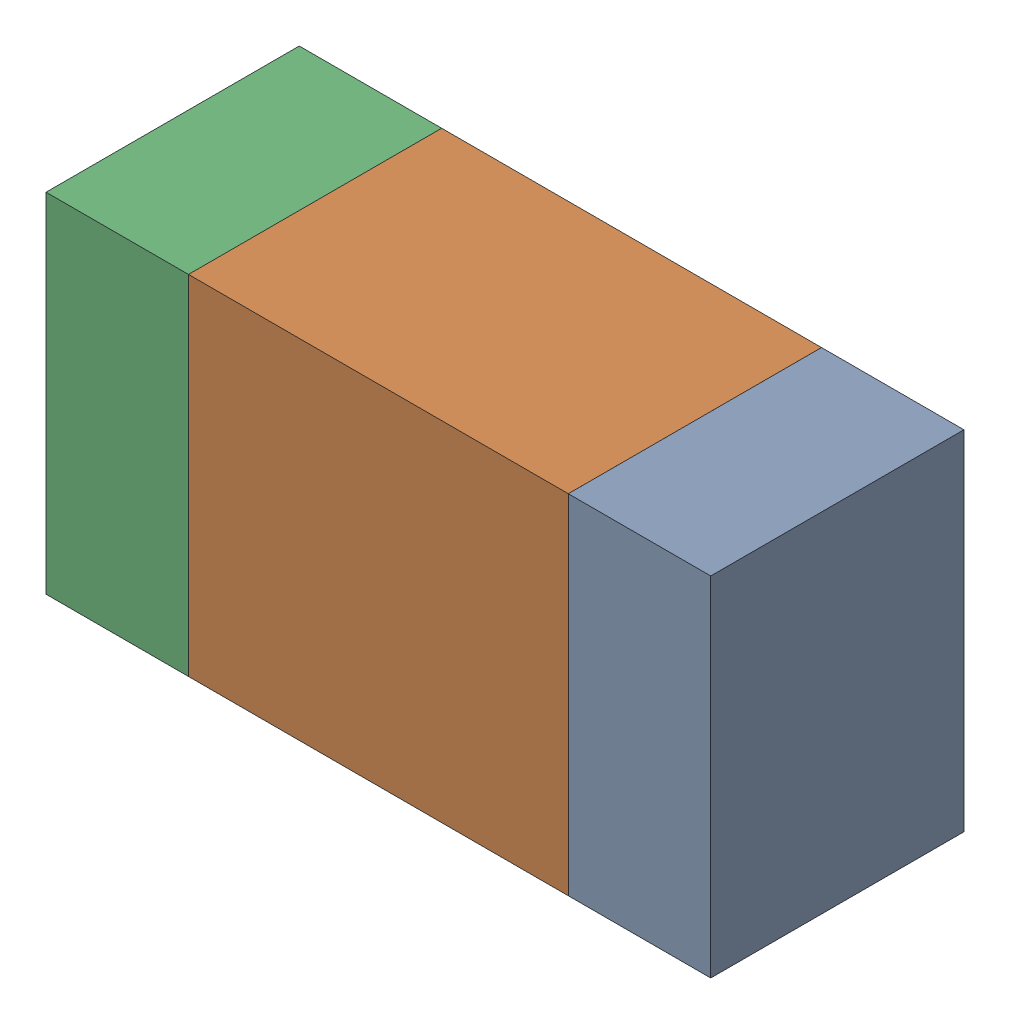
SolidWorks assembly R310_2PCB, configuration Default. Lengths in mm.
Overall size (1.05 0.55 0.4).
6 component instances, 2 part files, 0 mates.
Components (placement in the parent):
- 854785432-1: 854785432 [Default] at (133.6126 93.2999 -2.0638) size (0.22 0.55 0.4)
  - Extruded-1: Extruded [Default] at origin size (0.22 0.55 0.4)
- 854785568-1: 854785568 [Default] at (133.2001 93.2999 -2.0638) size (0.6 0.55 0.4)
  - Extruded_2-1: Extruded_2 [Default] at origin size (0.6 0.55 0.4)
- 854785432-2: 854785432 [Default] at (132.7876 93.2999 -2.0638) size (0.22 0.55 0.4)
  - Extruded-1: Extruded [Default] at origin size (0.22 0.55 0.4)
